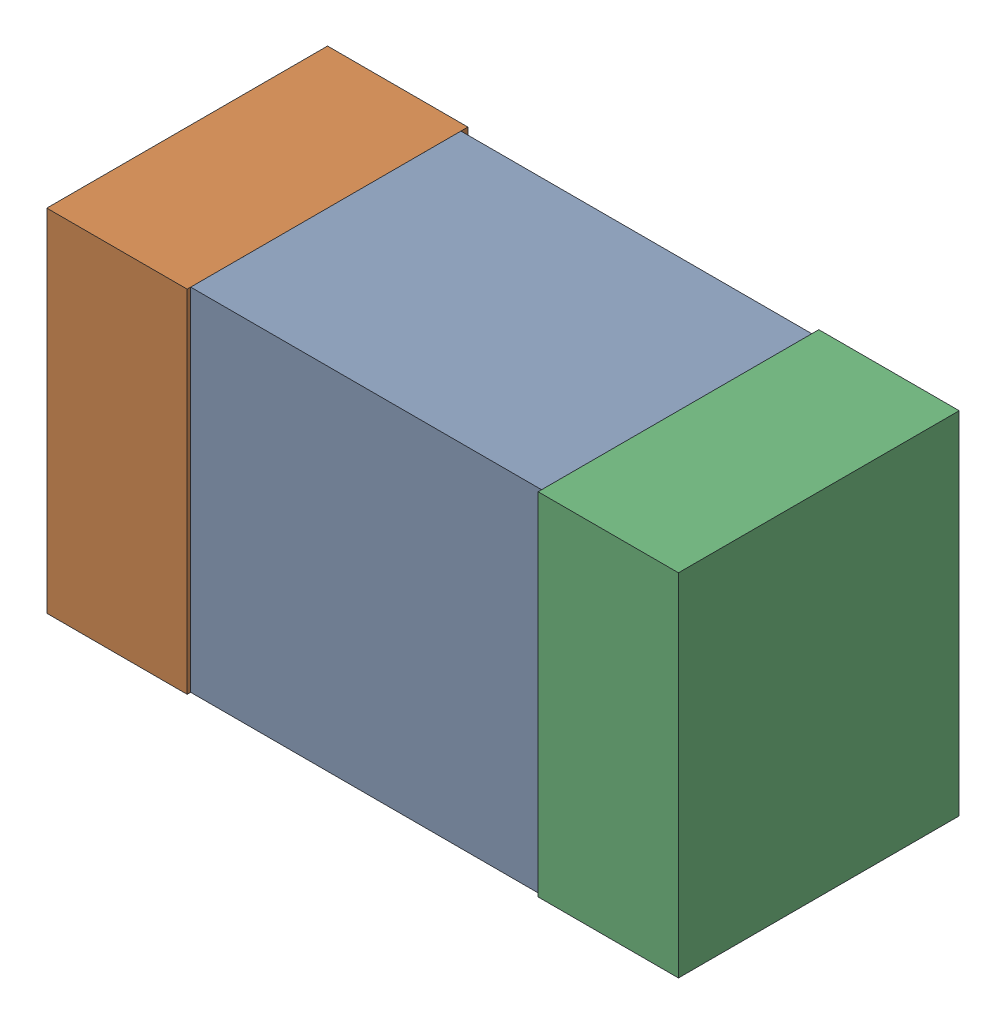
SolidWorks assembly L403PCB, configuration Default. Lengths in mm.
Overall size (1.8 1 0.8).
6 component instances, 2 part files, 0 mates.
Components (placement in the parent):
- 846483152-1: 846483152 [Default] at (115.6001 105.7999 -2.4438) size (1 1 0.77)
  - Extruded_3-1: Extruded_3 [Default] at origin size (1 1 0.77)
- 854785840-1: 854785840 [Default] at (114.9001 105.7999 -2.4638) size (0.4 1 0.8)
  - Extruded_4-1: Extruded_4 [Default] at origin size (0.4 1 0.8)
- 854785840-2: 854785840 [Default] at (116.3001 105.7999 -2.4638) size (0.4 1 0.8)
  - Extruded_4-1: Extruded_4 [Default] at origin size (0.4 1 0.8)
